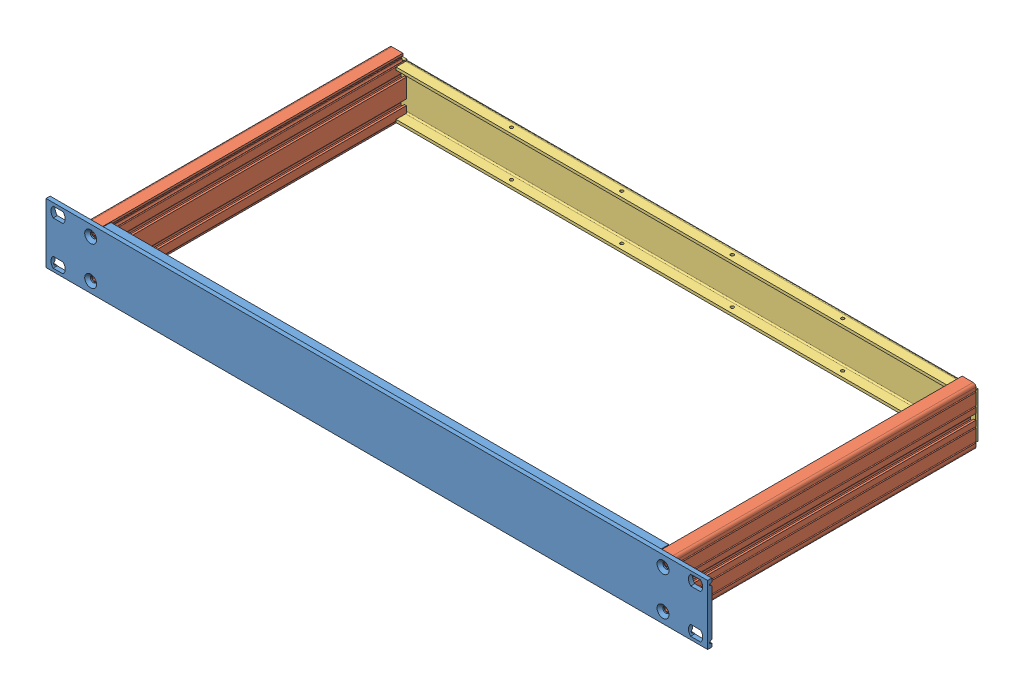
SolidWorks assembly 20860-201, configuration По умолчанию. Lengths in mm.
Overall size (482.6 43.65 225).
4 component instances, 3 part files, 0 mates.
Components (placement in the parent):
- 19-Z-FRONTPLATTE-1HE-1: 19-Z-FRONTPLATTE-1HE [По умолчанию] at (208.75 -8.2 0) size (482.6 43.65 9.5)
- 30860540-1: 30860540 [По умолчанию] at (21.5674 32.1357 -220) x (-1 0 0) z (0 0 1) size (12.5 41.6 220)
- 30860485-1: 30860485 [По умолчанию] at (67.7836 21.9728 -222) x (-1 0 0) z (0 0 -1) size (427 35.1 10)
- 30860540-2: 30860540 [По умолчанию] at (395.9318 32.1348 0) x (1 0 0) z (0 0 -1) size (12.5 41.6 220)
